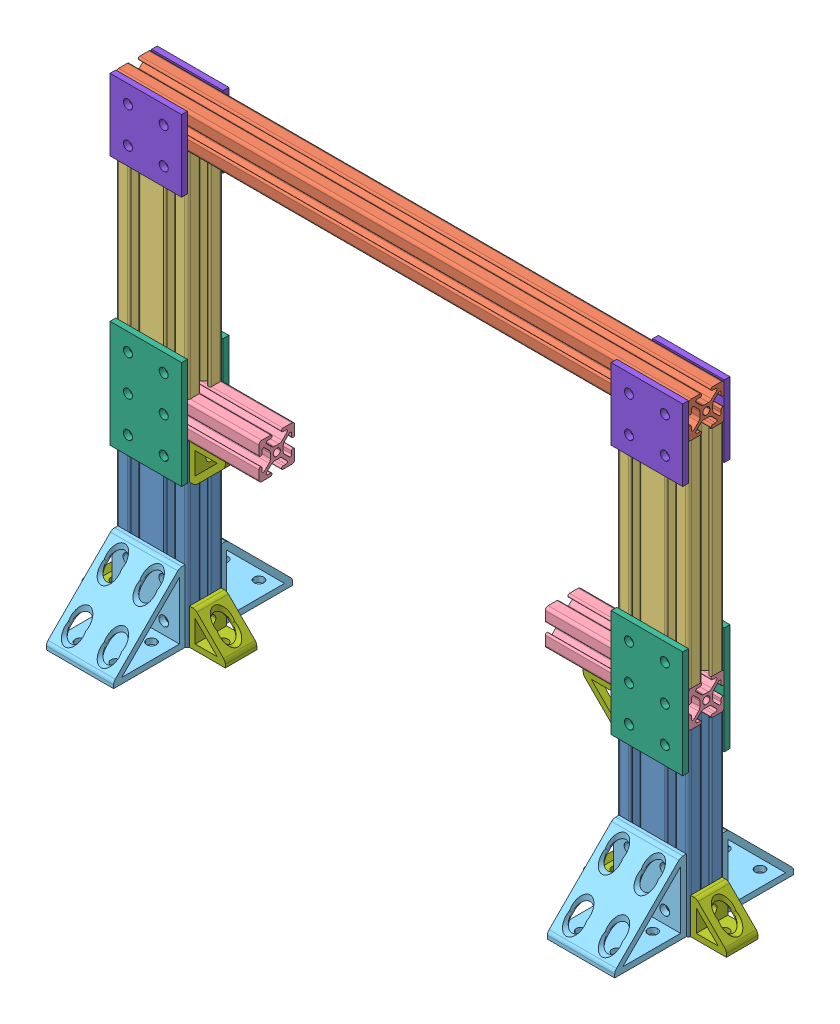
SolidWorks assembly Frame, configuration Default. Lengths in mm.
Overall size (450 325 125).
25 component instances, 8 part files, 54 mates.
Components (placement in the parent):
- 25_2550_125_CL-3: 25_2550_125_CL [Default] at (187.5 0 0) x (0 0 1) z (0 -1 0) size (25 50 125)
- 25_2550_125_CL-4: 25_2550_125_CL [Default] at (-162.5 0 0) x (0 0 1) z (0 -1 0) size (25 50 125)
- 25_2525_400_CL-1: 25_2525_400_CL [Default] at (-200 312.5 0) x (0 0 1) z (-1 0 0) size (25 25 400)
- 25_2550_150_CL-1: 25_2550_150_CL [Default] at (187.5 150 0) x (0 0 1) z (0 -1 0) size (25 50 150)
- 25_2550_150_CL-2: 25_2550_150_CL [Default] at (-187.5 300 0) x (0 0 1) z (0 1 0) size (25 50 150)
- 25_2525_100_CL-1: 25_2525_100_CL [Default] at (-200 137.5 0) x (0 0 1) z (-1 0 0) size (25 25 100)
- 25_2525_100_CL-2: 25_2525_100_CL [Default] at (100 137.5 0) x (0 0 1) z (-1 0 0) size (25 25 100)
- 25_4138-1: 25_4138 [Default] at (175 0 12.5) size (47 50 50)
- 25_4138-2: 25_4138 [Default] at (175 0 -12.5) x (-1 0 0) z (0 0 -1) size (47 50 50)
- 25_4166-1: 25_4166 [Default] at (175 100 -12.5) x (-1 0 0) z (0 0 -1) size (50 75 4)
- 25_4166-2: 25_4166 [Default] at (175 100 16.5) x (-1 0 0) z (0 0 -1) size (50 75 4)
- 25_4132-1: 25_4132 [Default] at (200 0 0) x (0 0 -1) z (1 0 0) size (22 25 25)
- 25_4132-2: 25_4132 [Default] at (150 0 0) x (0 0 1) z (-1 0 0) size (22 25 25)
- 25_4132-3: 25_4132 [Default] at (150 125 0) x (0 0 -1) z (-1 0 0) size (22 25 25)
- 25_4167-1: 25_4167 [Default] at (175 275 -16.5) size (50 50 4)
- 25_4167-2: 25_4167 [Default] at (175 275 12.5) size (50 50 4)
- 25_4166-3: 25_4166 [Default] at (-175 100 -16.5) size (50 75 4)
- 25_4138-3: 25_4138 [Default] at (-175 0 -12.5) x (-1 0 0) z (0 0 -1) size (47 50 50)
- 25_4132-4: 25_4132 [Default] at (-200 0 0) x (0 0 1) z (-1 0 0) size (22 25 25)
- 25_4138-4: 25_4138 [Default] at (-175 0 12.5) size (47 50 50)
- 25_4166-4: 25_4166 [Default] at (-175 100 12.5) size (50 75 4)
- 25_4167-3: 25_4167 [Default] at (-175 275 -12.5) x (-1 0 0) z (0 0 -1) size (50 50 4)
- 25_4167-4: 25_4167 [Default] at (-175 275 16.5) x (-1 0 0) z (0 0 -1) size (50 50 4)
- 25_4132-5: 25_4132 [Default] at (-150 125 0) x (0 0 1) z (1 0 0) size (22 25 25)
- 25_4132-6: 25_4132 [Default] at (-150 0 0) x (0 0 -1) z (1 0 0) size (22 25 25)
Mates (geometry in assembly coordinates):
- Coincident1: coincident anti-aligned: plane of 25_2550_125_CL-3 through (158.18 0 -11.43) normal (0 -1 0)
- Coincident2: coincident anti-aligned: plane of 25_2550_125_CL-4 through (-191.82 0 -11.43) normal (0 -1 0)
- Coincident3: coincident aligned: plane of 25_2550_125_CL-3 through (183.18 125 12.5) normal (0 0 1); plane of 25_2550_125_CL-4 through (-166.82 125 12.5) normal (0 0 1)
- Coincident7: coincident aligned: plane of 25_2550_125_CL-4 through (-166.82 125 12.5) normal (0 0 1); plane of 25_2525_400_CL-1 through (200 301.9629 12.5) normal (0 0 1)
- Coincident9: coincident anti-aligned: plane of 25_2525_400_CL-1 through (200 300 4.3879) normal (0 -1 0); plane of 25_2550_150_CL-2 through (-158.18 300 -11.43) normal (0 1 0)
- Coincident10: coincident aligned: plane of 25_2525_400_CL-1 through (200 316.82 12.5) normal (0 0 1); plane of 25_2550_150_CL-2 through (-183.18 150 12.5) normal (0 0 1)
- Coincident11: coincident aligned: plane of 25_2550_125_CL-4 through (-166.82 125 12.5) normal (0 0 1); plane of 25_2550_150_CL-2 through (-183.18 150 12.5) normal (0 0 1)
- Coincident12: coincident aligned: plane of 25_2550_125_CL-3 through (183.18 125 12.5) normal (0 0 1); plane of 25_2525_400_CL-1 through (200 316.82 12.5) normal (0 0 1)
- Coincident13: coincident aligned: plane of 25_2550_125_CL-3 through (183.18 125 12.5) normal (0 0 1); plane of 25_2550_150_CL-1 through (183.18 300 12.5) normal (0 0 1)
- Coincident14: coincident anti-aligned: plane of 25_2525_400_CL-1 through (200 300 4.3879) normal (0 -1 0); plane of 25_2550_150_CL-1 through (158.18 300 -11.43) normal (0 1 0)
- Coincident15: coincident aligned: plane of 25_2525_400_CL-1 through (-200 316.82 -11.43) normal (-1 0 0); plane of 25_2550_150_CL-2 through (-200 150 4.32) normal (-1 0 0)
- Coincident16: coincident aligned: plane of 25_2550_125_CL-4 through (-200 125 -4.32) normal (-1 0 0); plane of 25_2550_150_CL-2 through (-200 150 -10.469) normal (-1 0 0)
- Coincident17: coincident aligned: plane of 25_2525_400_CL-1 through (200 316.82 -11.43) normal (1 0 0); plane of 25_2550_150_CL-1 through (200 300 4.32) normal (1 0 0)
- Coincident18: coincident aligned: plane of 25_2550_125_CL-3 through (200 125 -10.469) normal (1 0 0); plane of 25_2550_150_CL-1 through (200 300 -10.469) normal (1 0 0)
- Coincident19: coincident anti-aligned: plane of 25_2550_150_CL-2 through (-158.18 150 -11.43) normal (0 -1 0); plane of 25_2525_100_CL-1 through (-100 150 -4.32) normal (0 1 0)
- Coincident20: coincident anti-aligned: plane of 25_2550_125_CL-4 through (-191.82 125 -11.43) normal (0 1 0); plane of 25_2525_100_CL-1 through (-100 125 4.3879) normal (0 -1 0)
- Coincident21: coincident aligned: plane of 25_2550_150_CL-2 through (-197.969 150 12.5) normal (0 0 1); plane of 25_2525_100_CL-1 through (-100 141.82 12.5) normal (0 0 1)
- Coincident22: coincident aligned: plane of 25_2550_150_CL-2 through (-200 150 4.32) normal (-1 0 0); plane of 25_2525_100_CL-1 through (-200 141.82 -11.43) normal (-1 0 0)
- Coincident23: coincident aligned: plane of 25_2550_150_CL-1 through (200 300 -10.469) normal (1 0 0); plane of 25_2525_100_CL-2 through (200 141.82 -11.43) normal (1 0 0)
- Coincident24: coincident aligned: plane of 25_2550_125_CL-3 through (183.18 125 12.5) normal (0 0 1); plane of 25_2525_100_CL-2 through (200 141.82 12.5) normal (0 0 1)
- Coincident25: coincident anti-aligned: plane of 25_2550_150_CL-1 through (158.18 150 -11.43) normal (0 -1 0); plane of 25_2525_100_CL-2 through (200 150 10.5371) normal (0 1 0)
- Coincident26: coincident anti-aligned: plane of 25_2550_125_CL-3 through (183.18 125 12.5) normal (0 0 1); plane of 25_4138-1 through (198.5 0 12.5) normal (0 0 -1)
- Coincident27: coincident aligned: plane of 25_2550_125_CL-3 through (158.18 0 -11.43) normal (0 -1 0); plane of 25_4138-1 through (198.5 0 62.5) normal (0 -1 0)
- Width1: width: cylinder of 25_2550_125_CL-3; plane of 25_4138-1 through (166.9 125 1.5737) normal (1 0 0); cylinder of 25_2550_125_CL-3 through (162.5 37.5 16.5) axis (0 0 -1) radius 3.405
- Coincident28: coincident anti-aligned: plane of 25_2550_125_CL-3 through (166.82 125 -12.5) normal (0 0 -1); plane of 25_4138-2 through (151.5 0 -12.5) normal (0 0 1)
- Coincident29: coincident aligned: plane of 25_2550_125_CL-3 through (158.18 0 -11.43) normal (0 -1 0); plane of 25_4138-2 through (151.5 0 -62.5) normal (0 -1 0)
- Width2: width: plane of 25_2550_125_CL-3 through (191.9 125 -1.5737) normal (1 0 0); plane of 25_4138-2 through (183.1 125 -1.5737) normal (-1 0 0); cylinder of 25_2550_125_CL-3 through (187.5 37.5 -16.5) axis (0 0 1) radius 3.405
- Coincident30: coincident anti-aligned: plane of 25_2550_150_CL-1 through (166.82 300 -12.5) normal (0 0 -1); plane of 25_4166-1 through (175 100 -12.5) normal (0 0 1)
- Width3: width: plane of 25_2550_150_CL-1 through (191.9 300 -1.5737) normal (1 0 0); plane of 25_4166-1 through (183.1 300 -1.5737) normal (-1 0 0); cylinder of 25_2550_150_CL-1 through (187.5 162.5 -16.5) axis (0 0 1) radius 3.175
- Width4: width: plane of 25_2525_100_CL-2 through (200 141.875 1.5554) normal (0 1 0); plane of 25_4166-1 through (200 133.125 -1.5554) normal (0 -1 0); cylinder of 25_2525_100_CL-2 through (187.5 137.5 -16.5) axis (0 0 1) radius 3.175
- Parallel1: parallel aligned: plane of 25_2550_125_CL-3 through (200 125 -10.469) normal (1 0 0); plane of 25_4166-1 through (200 175 -16.5) normal (1 0 0)
- Coincident31: coincident anti-aligned: plane of 25_2550_150_CL-1 through (183.18 300 12.5) normal (0 0 1); plane of 25_4166-2 through (175 100 12.5) normal (0 0 -1)
- Parallel2: parallel aligned: plane of 25_2550_150_CL-1 through (200 300 4.32) normal (1 0 0); plane of 25_4166-2 through (200 175 12.5) normal (1 0 0)
- Symmetric1: symmetric aligned: plane of 25_2550_150_CL-1 through (200 300 -10.469) normal (1 0 0); plane of 25_2550_150_CL-2 through (-200 150 -10.469) normal (-1 0 0)
- Symmetric2: symmetric aligned: plane of 25_2525_400_CL-1 through (200 323.0371 -12.5) normal (0 0 -1); plane of 25_2525_400_CL-1 through (200 316.82 12.5) normal (0 0 1)
- Width5: width: plane of 25_2550_150_CL-1 through (158.1 300 1.5737) normal (-1 0 0); plane of 25_4166-2 through (166.9 300 1.5737) normal (1 0 0); cylinder of 25_2550_150_CL-1 through (162.5 162.5 12.5) axis (0 0 1) radius 3.175
- Width6: width: plane of 25_2525_100_CL-2 through (200 141.875 1.5554) normal (0 1 0); plane of 25_4166-2 through (200 133.125 -1.5554) normal (0 -1 0); cylinder of 25_2525_100_CL-2 through (162.5 137.5 12.5) axis (0 0 1) radius 3.175
- Coincident33: coincident anti-aligned: plane of 25_2550_125_CL-3 through (200 125 4.32) normal (1 0 0); plane of 25_4132-1 through (200 0 -11) normal (-1 0 0)
- Coincident34: coincident aligned: plane of 25_2550_125_CL-3 through (158.18 0 -11.43) normal (0 -1 0); plane of 25_4132-1 through (225 0 -11) normal (0 -1 0)
- Width7: width: plane of 25_2550_125_CL-3 through (185.9263 125 -4.4) normal (0 0 -1); plane of 25_4132-1 through (189.0737 125 4.4) normal (0 0 1); cylinder of 25_2550_125_CL-3 through (212.5 4 0) axis (0 -1 0) radius 3.405
- Coincident35: coincident anti-aligned: plane of 25_2550_125_CL-3 through (150 125 10.469) normal (-1 0 0); plane of 25_4132-2 through (150 0 11) normal (1 0 0)
- Coincident36: coincident aligned: plane of 25_2550_125_CL-3 through (158.18 0 -11.43) normal (0 -1 0); plane of 25_4132-2 through (125 0 11) normal (0 -1 0)
- Width8: width: plane of 25_2550_125_CL-3 through (164.0737 125 4.4) normal (0 0 1); plane of 25_4132-2 through (160.9263 125 -4.4) normal (0 0 -1); cylinder of 25_2550_125_CL-3 through (137.5 4 0) axis (0 -1 0) radius 3.405
- Coincident37: coincident anti-aligned: plane of 25_2550_125_CL-3 through (150 125 10.469) normal (-1 0 0); plane of 25_4132-3 through (150 125 -11) normal (1 0 0)
- Coincident38: coincident anti-aligned: plane of 25_2525_100_CL-2 through (200 125 -10.5371) normal (0 -1 0); plane of 25_4132-3 through (125 125 -11) normal (0 1 0)
- Width9: width: plane of 25_2550_125_CL-3 through (152.031 125 -12.5) normal (0 0 -1); plane of 25_4132-3 through (158.18 125 12.5) normal (0 0 1); cylinder of 25_2550_125_CL-3 through (146 112.5 0) axis (1 0 0) radius 3.405
- Coincident39: coincident anti-aligned: plane of 25_2550_150_CL-1 through (166.82 300 -12.5) normal (0 0 -1); plane of 25_4167-1 through (175 275 -12.5) normal (0 0 1)
- Coincident40: coincident anti-aligned: plane of 25_2550_150_CL-1 through (183.18 300 12.5) normal (0 0 1); plane of 25_4167-2 through (175 275 12.5) normal (0 0 -1)
- Width10: width: plane of 25_2550_150_CL-1 through (191.9 300 -1.5737) normal (1 0 0); plane of 25_4167-2 through (183.1 300 -1.5737) normal (-1 0 0); cylinder of 25_2550_150_CL-1 through (187.5 287.5 16.5) axis (0 0 -1) radius 3.175
- Parallel5: parallel aligned: plane of 25_2550_150_CL-1 through (200 300 4.32) normal (1 0 0); plane of 25_4167-2 through (200 275 16.5) normal (1 0 0)
- Width11: width: plane of 25_2525_400_CL-1 through (200 316.875 1.5554) normal (0 1 0); plane of 25_4167-2 through (200 308.125 -1.5554) normal (0 -1 0); cylinder of 25_2525_400_CL-1 through (187.5 312.5 16.5) axis (0 0 -1) radius 3.175
- Width12: width: plane of 25_2550_150_CL-1 through (158.1 300 1.5737) normal (-1 0 0); plane of 25_4167-1 through (166.9 300 1.5737) normal (1 0 0); cylinder of 25_2550_150_CL-1 through (162.5 287.5 -12.5) axis (0 0 -1) radius 3.175
- Parallel6: parallel aligned: plane of 25_2550_150_CL-1 through (150 300 -4.32) normal (-1 0 0); plane of 25_4167-1 through (150 325 -12.5) normal (-1 0 0)
- Width13: width: plane of 25_2525_400_CL-1 through (200 316.875 1.5554) normal (0 1 0); plane of 25_4167-1 through (200 308.125 -1.5554) normal (0 -1 0); cylinder of 25_2525_400_CL-1 through (187.5 312.5 -12.5) axis (0 0 -1) radius 3.175
